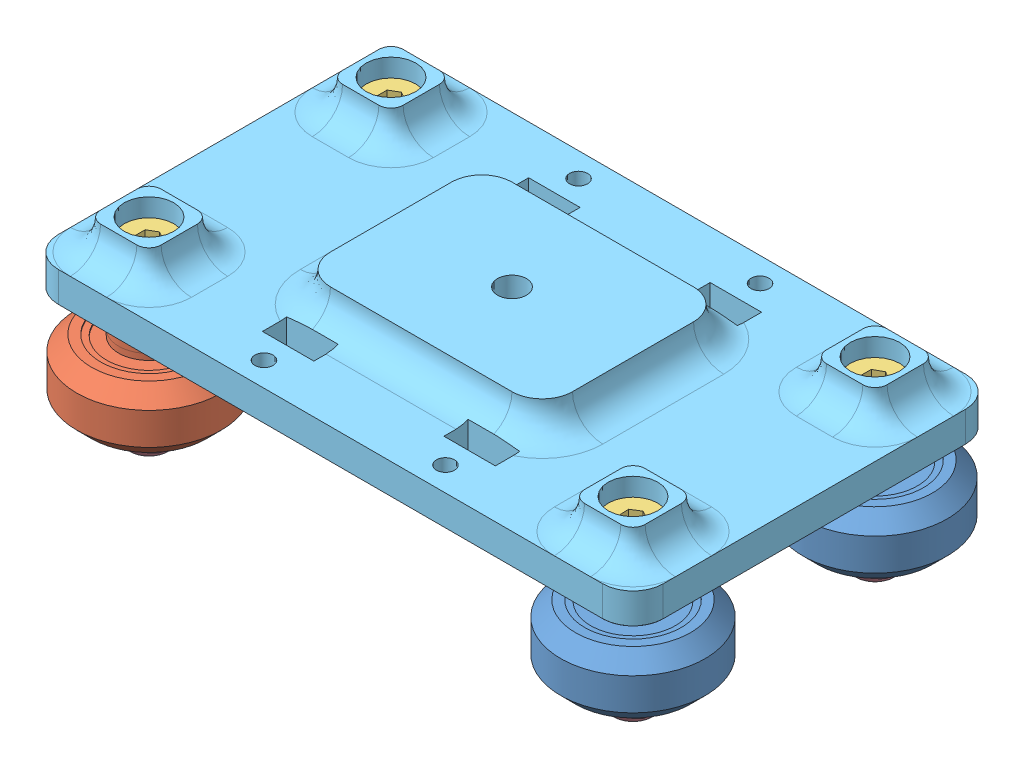
SolidWorks assembly VSlotGantryAssembly2, configuration Default. Lengths in mm.
Overall size (108.85 32 72.56).
13 component instances, 5 part files, 38 mates.
Components (placement in the parent):
- V-Wheel Solid Wheel-1: V-Wheel Solid Wheel [Default] at (76.3282 31.8437 123.3877) x (-0.38895 0 -0.921259) z (-0.921259 0 0.38895) size (23.9 20 23.9)
- V-Wheel Solid Wheel-2: V-Wheel Solid Wheel [Default] at (87.9897 31.8437 111.6656) x (0.696587 0 0.717472) z (0.717472 0 -0.696587) size (23.9 20 23.9)
- V-Wheel Solid Wheel - spacer-1: V-Wheel Solid Wheel - spacer [Default] at (-15.7649 31.8437 95.6225) x (-1 0 0) z (0 0 1) size (23.9 17 23.9)
- V-Wheel Solid Wheel - spacer-2: V-Wheel Solid Wheel - spacer [Default] at (-15.7649 29.8437 135.6225) x (-1 0 0) z (0 0 1) size (23.9 17 23.9)
- M5x25 low profile screw-1: M5x25 low profile screw [Default] at (-0.4953 49.5148 98.6213) x (1 0 0) z (0 -1 0) size (11 11 27)
- M5x25 low profile screw-2: M5x25 low profile screw [Default] at (-0.4953 49.5148 138.6213) x (1 0 0) z (0 -1 0) size (11 11 27)
- M5x25 low profile screw-3: M5x25 low profile screw [Default] at (79.5047 49.5148 98.6213) x (0.999976 0 0.00694) z (0 -1 0) size (11 11 27)
- M5x25 low profile screw-4: M5x25 low profile screw [Default] at (79.5047 49.5148 138.6213) x (0.999419 0 -0.034076) z (0 -1 0) size (11 11 27)
- M5 Nylock-1: M5 Nylock [Default] at (-0.4953 25.5148 138.6213) x (-1 0 0) z (0 -1 0) size (8.02 9.26 5)
- M5 Nylock-2: M5 Nylock [Default] at (-0.4953 27.5148 98.6213) x (-1 0 0) z (0 -1 0) size (8.02 9.26 5)
- M5 Nylock-3: M5 Nylock [Default] at (79.5047 27.5148 98.6213) x (-1 0 0) z (0 -1 0) size (8.02 9.26 5)
- M5 Nylock-4: M5 Nylock [Default] at (79.5047 27.5148 138.6213) x (-1 0 0) z (0 -1 0) size (8.02 9.26 5)
- GantryPlatev2-1: GantryPlatev2 [Default] at (39.5047 42.5148 118.6213) x (-1 0 0) z (0 1 0) size (100 60 10)
Mates (geometry in assembly coordinates):
- Coincident1: coincident anti-aligned: plane of BasePlate-1 through (-9.6178 54.251 64.1751) normal (0 -1 0); plane of V-Wheel Solid Wheel - spacer-2 through (9.4244 51.34 133.2867) normal (0 1 0)
- Concentric1: concentric anti-aligned: circle of BasePlate-1; circle of V-Wheel Solid Wheel - spacer-2
- Coincident2: coincident anti-aligned: plane of BasePlate-1 through (-9.6178 54.251 64.1751) normal (0 -1 0); plane of V-Wheel Solid Wheel - spacer-1 through (9.4244 53.1928 93.2867) normal (0 1 0)
- Concentric2: concentric anti-aligned: cylinder of BasePlate-1; cylinder of V-Wheel Solid Wheel - spacer-1 through (9.4244 47.1928 93.2867) axis (0 -1 0) radius 2.55
- Coincident3: coincident anti-aligned: plane of BasePlate-1 through (-9.6178 54.251 64.1751) normal (0 -1 0); plane of V-Wheel Solid Wheel-2 through (88.7994 54.251 73.7351) normal (0 1 0)
- Coincident5: coincident anti-aligned: plane of BasePlate-1 through (-9.6178 54.251 64.1751) normal (0 -1 0); plane of V-Wheel Solid Wheel-1 through (88.9146 54.251 133.7351) normal (0 1 0)
- Tangent2: tangent anti-aligned: plane of BasePlate-1 through (78.8822 59.251 70.1751) normal (0 0 1); cylinder of V-Wheel Solid Wheel-2 through (88.7994 51.251 73.7351) axis (0 -1 0) radius 3.56
- Tangent3: tangent anti-aligned: plane of BasePlate-1 through (78.8822 59.251 130.1751) normal (0 0 1); cylinder of V-Wheel Solid Wheel-1 through (88.9146 51.251 133.7351) axis (0 -1 0) radius 3.56
- Coincident6: coincident anti-aligned: plane of BasePlate-1 through (-9.6178 59.251 64.1751) normal (0 1 0); plane of M5x25 low profile screw-2 through (9.4244 58.6273 138.7867) normal (0 -1 0)
- Concentric5: concentric anti-aligned: circle of BasePlate-1; cylinder of M5x25 low profile screw-2 through (9.4244 46.1273 133.2867) axis (0 -1 0) radius 2.5
- Coincident7: coincident anti-aligned: plane of BasePlate-1 through (-9.6178 59.251 64.1751) normal (0 1 0); plane of M5x25 low profile screw-1 through (9.4244 61.34 98.7867) normal (0 -1 0)
- Concentric6: concentric anti-aligned: circle of BasePlate-1; cylinder of M5x25 low profile screw-1 through (9.4244 48.84 93.2867) axis (0 -1 0) radius 2.5
- Coincident8: coincident anti-aligned: plane of BasePlate-1 through (-9.6178 59.251 64.1751) normal (0 1 0); plane of M5x25 low profile screw-4 through (89.102 59.251 139.2319) normal (0 -1 0)
- Concentric7: concentric anti-aligned: cylinder of V-Wheel Solid Wheel-1 through (79.5047 47.5148 138.6213) axis (0 1 0) radius 2.5; cylinder of M5x25 low profile screw-4 through (79.5047 35.0148 138.6213) axis (0 -1 0) radius 2.5
- Coincident9: coincident anti-aligned: plane of BasePlate-1 through (-9.6178 59.251 64.1751) normal (0 1 0); plane of M5x25 low profile screw-3 through (88.7613 59.251 79.235) normal (0 -1 0)
- Concentric8: concentric anti-aligned: cylinder of V-Wheel Solid Wheel-2 through (79.5047 6.5204 98.6213) axis (0 1 0) radius 2.5; cylinder of M5x25 low profile screw-3 through (79.5047 35.0148 98.6213) axis (0 -1 0) radius 2.5
- Coincident10: coincident anti-aligned: plane of V-Wheel Solid Wheel - spacer-2 through (-3.3478 25.5148 136.5931) normal (0 -1 0); plane of M5 Nylock-1 through (-0.4953 25.5148 138.6213) normal (0 1 0)
- Concentric9: concentric anti-aligned: cylinder of M5x25 low profile screw-2 through (-0.4953 35.0148 138.6213) axis (0 -1 0) radius 2.5; cylinder of M5 Nylock-1 through (-0.4953 25.5148 138.6213) axis (0 1 0) radius 2.5
- Coincident12: coincident anti-aligned: plane of V-Wheel Solid Wheel - spacer-1 through (-3.3478 27.5148 96.5931) normal (0 -1 0); plane of M5 Nylock-2 through (-0.4953 27.5148 98.6213) normal (0 1 0)
- Concentric10: concentric anti-aligned: cylinder of M5x25 low profile screw-1 through (-0.4953 35.0148 98.6213) axis (0 -1 0) radius 2.5; cylinder of M5 Nylock-2 through (-0.4953 27.5148 98.6213) axis (0 1 0) radius 2.5
- Coincident13: coincident anti-aligned: plane of V-Wheel Solid Wheel-1 through (80.2636 27.5148 135.2046) normal (0 -1 0); plane of M5 Nylock-4 through (79.5047 27.5148 138.6213) normal (0 1 0)
- Concentric11: concentric anti-aligned: cylinder of M5x25 low profile screw-4 through (79.5047 35.0148 138.6213) axis (0 -1 0) radius 2.5; cylinder of M5 Nylock-4 through (79.5047 27.5148 138.6213) axis (0 1 0) radius 2.5
- Coincident14: coincident anti-aligned: plane of V-Wheel Solid Wheel-2 through (80.0365 -13.4796 102.0806) normal (0 -1 0); plane of M5 Nylock-3 through (79.5047 -13.4796 98.6213) normal (0 1 0)
- Concentric12: concentric anti-aligned: cylinder of M5x25 low profile screw-3 through (79.5047 35.0148 98.6213) axis (0 -1 0) radius 2.5; cylinder of M5 Nylock-3 through (79.5047 -13.4796 98.6213) axis (0 1 0) radius 2.5
- Coincident15: coincident anti-aligned: plane of V-Wheel Solid Wheel - spacer-2 through (-0.4953 42.5148 138.6213) normal (0 1 0); plane of GantryPlatev2-1 through (-5.4953 42.5148 143.6213) normal (0 -1 0)
- Concentric13: concentric anti-aligned: cylinder of M5x25 low profile screw-2 through (-0.4953 35.0148 138.6213) axis (0 -1 0) radius 2.5; cylinder of GantryPlatev2-1 through (-0.4953 35.9182 138.6213) axis (0 1 0) radius 4.1
- Concentric14: concentric aligned: cylinder of V-Wheel Solid Wheel - spacer-2 through (-0.4953 36.5148 138.6213) axis (0 -1 0) radius 2.55; cylinder of M5x25 low profile screw-2 through (-0.4953 35.0148 138.6213) axis (0 -1 0) radius 2.5
- Concentric15: concentric anti-aligned: cylinder of M5x25 low profile screw-1 through (-0.4953 35.0148 98.6213) axis (0 -1 0) radius 2.5; cylinder of GantryPlatev2-1 through (-0.4953 35.9182 98.6213) axis (0 1 0) radius 4.1
- Concentric16: concentric aligned: cylinder of V-Wheel Solid Wheel - spacer-1 through (-0.4953 38.5148 98.6213) axis (0 -1 0) radius 2.55; cylinder of M5x25 low profile screw-1 through (-0.4953 35.0148 98.6213) axis (0 -1 0) radius 2.5
- Coincident19: coincident aligned: plane of M5x25 low profile screw-1 through (-0.4953 22.5148 101.1213) normal (0 -1 0); plane of M5 Nylock-2 through (-0.4953 22.5148 98.6213) normal (0 -1 0)
- Coincident20: coincident anti-aligned: plane of M5x25 low profile screw-1 through (-0.4953 47.5148 104.1213) normal (0 -1 0); plane of GantryPlatev2-1 through (76.5047 47.5148 141.6213) normal (0 1 0)
- Coincident21: coincident anti-aligned: plane of M5x25 low profile screw-2 through (-0.4953 47.5148 144.1213) normal (0 -1 0); plane of GantryPlatev2-1 through (76.5047 47.5148 141.6213) normal (0 1 0)
- Coincident22: coincident anti-aligned: plane of M5x25 low profile screw-4 through (79.6921 47.5148 144.1181) normal (0 -1 0); plane of GantryPlatev2-1 through (76.5047 47.5148 141.6213) normal (0 1 0)
- Concentric17: concentric anti-aligned: cylinder of M5x25 low profile screw-4 through (79.5047 35.0148 138.6213) axis (0 -1 0) radius 2.5; cylinder of GantryPlatev2-1 through (79.5047 35.9182 138.6213) axis (0 1 0) radius 4.1
- Coincident23: coincident aligned: plane of M5x25 low profile screw-4 through (79.5898 22.5148 141.1198) normal (0 -1 0); plane of M5 Nylock-4 through (79.5047 22.5148 138.6213) normal (0 -1 0)
- Coincident24: coincident anti-aligned: plane of M5x25 low profile screw-3 through (79.4665 47.5148 104.1211) normal (0 -1 0); plane of GantryPlatev2-1 through (76.5047 47.5148 141.6213) normal (0 1 0)
- Concentric18: concentric anti-aligned: cylinder of M5x25 low profile screw-3 through (79.5047 35.0148 98.6213) axis (0 -1 0) radius 2.5; cylinder of GantryPlatev2-1 through (79.5047 35.9182 98.6213) axis (0 1 0) radius 4.1
- Coincident26: coincident aligned: plane of M5x25 low profile screw-3 through (79.4873 22.5148 101.1212) normal (0 -1 0); plane of M5 Nylock-3 through (79.5047 22.5148 98.6213) normal (0 -1 0)
